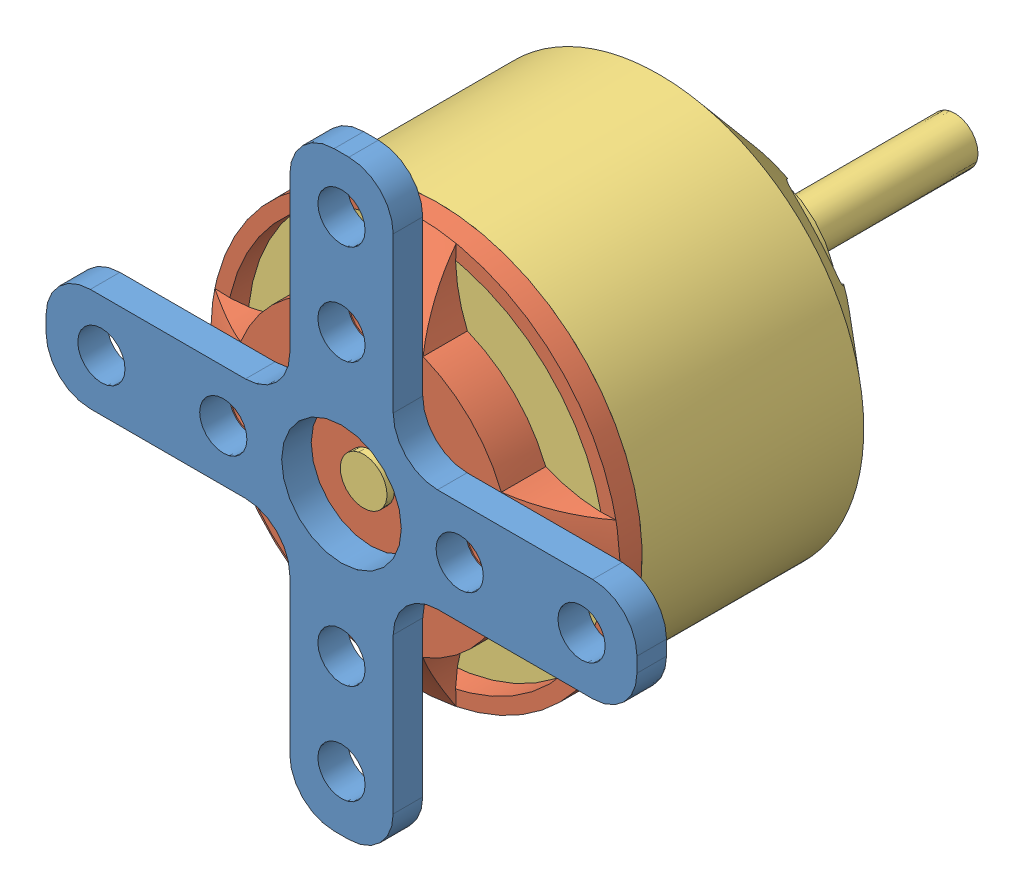
SolidWorks assembly MotorySoporteNuevo, configuration Predeterminado. Lengths in mm.
Overall size (41.48 41.48 41.5).
4 component instances, 3 part files, 4 mates.
Components (placement in the parent):
- Soporte motor-1: Soporte motor [Predeterminado] at origin size (40 40 2)
- Motor Brushless con base-1: Motor Brushless con base [Default] at (3.4256 -24.7691 9.7644) x (0.707107 0.707107 0) z (-0.707107 0.707107 0) size (29.33 40 29.33)
  - MotorAltKısım-1: MotorAltKısım [Default] at (15.0921 9.1644 83.5045) size (27.7 4.63 27.7)
  - MotorUst-1: MotorUst [Default] at (15.0921 10.2644 19.9367) x (0.998155 0 -0.060719) z (0.060719 0 0.998155) size (27.7 40 27.7)
Mates (geometry in assembly coordinates):
- Coincidente4: coincident anti-aligned: plane of Soporte motor-1 through (-0.2981 -23.1968 42.0175) normal (0 1 0); plane of Motor Brushless con base-1/MotorAltKısım-1 through (-0.2981 -23.1968 42.0175) normal (0 -1 0)
- Concéntrica1: concentric aligned: circle of Soporte motor-1; circle of Motor Brushless con base-1/MotorAltKısım-1
- Concéntrica2: concentric aligned: circle of Soporte motor-1; circle of Motor Brushless con base-1/MotorAltKısım-1
- Coincidente5: coordinate: point of Soporte motor-1
